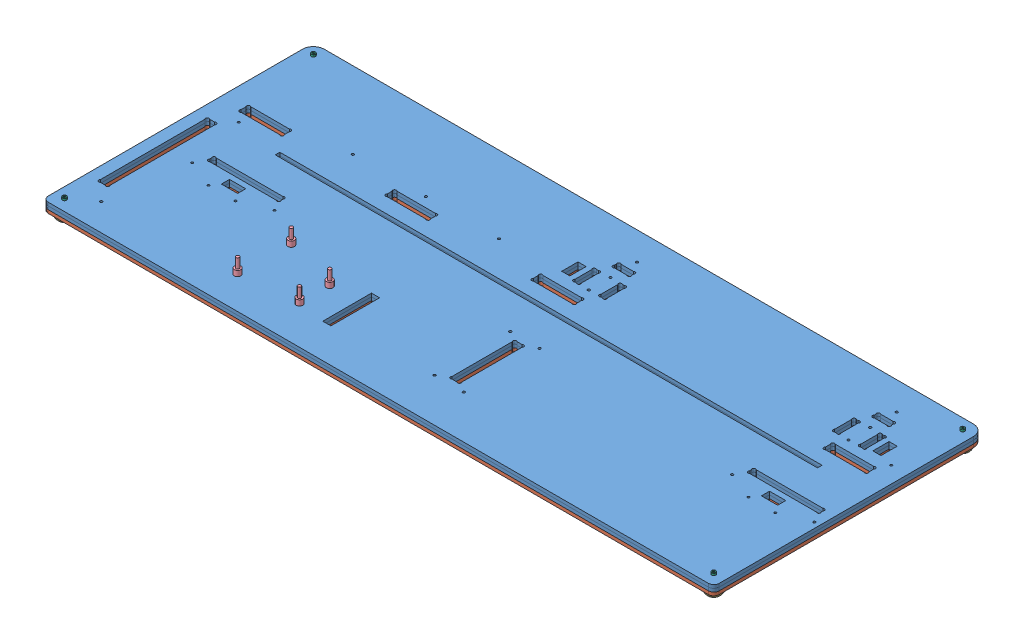
SolidWorks assembly socle-complet, configuration Défaut. Lengths in mm.
Overall size (621.62 30.74 251.62).
21 component instances, 6 part files, 49 mates.
Components (placement in the parent):
- socle-1-1: socle-1 [Défaut] at (-302.5453 40.1785 745) size (620 3 250)
- socle-1-2: socle-1 [Défaut] at (-302.5453 37.1785 745) size (620 3 250)
- socle-2-3: socle-2 [Défaut] at (-302.5453 34.1785 745) size (620 3 250)
- socle-patin-ecrou_m2-1: socle-patin-ecrou_m2 [Défaut] at (-292.5453 34.1785 735) x (0.367083 0 0.930188) z (-0.930188 0 0.367083) size (16 7.74 16)
- socle-patin-ecrou_m2-2: socle-patin-ecrou_m2 [Défaut] at (-292.5453 34.1785 505) x (-0.622025 0 0.782997) z (-0.782997 0 -0.622025) size (16 7.74 16)
- socle-patin-ecrou_m2-3: socle-patin-ecrou_m2 [Défaut] at (307.4547 34.1785 505) x (0.367083 0 0.930188) z (-0.930188 0 0.367083) size (16 7.74 16)
- socle-patin-ecrou_m2-4: socle-patin-ecrou_m2 [Défaut] at (307.4547 34.1785 735) x (0.367083 0 0.930188) z (-0.930188 0 0.367083) size (16 7.74 16)
- socle-carte_pied-1: socle-carte_pied [Défaut] at (-152.5453 38.1785 715) x (0 1 0) z (-0.920347 0 -0.391102) size (19 6 6)
- socle-carte_pied-2: socle-carte_pied [Défaut] at (-151.2753 38.1785 666.74) x (0 1 0) z (-0.842592 0 -0.538553) size (19 6 6)
- socle-carte_pied-3: socle-carte_pied [Défaut] at (-100.4753 38.1785 681.98) x (0 1 0) z (-0.819102 0 -0.573647) size (19 6 6)
- socle-carte_pied-4: socle-carte_pied [Défaut] at (-100.4753 38.1785 709.92) x (0 1 0) z (0.984574 0 0.174968) size (19 6 6)
- ecrou-h-1: ecrou-h [6007 HU M2] at (-292.5453 31.1785 735) size (4 1.6 4.62)
- vis-chc-1: vis-chc [Vis CHC M2x16] at (-292.5453 43.1785 735) x (0.999999 0 -0.001395) z (0.001395 0 0.999999) size (3.8 18 3.8)
- vis-chc-2: vis-chc [Vis CHC M2x16] at (307.4547 43.1785 735) x (0.999999 0 -0.001395) z (0.001395 0 0.999999) size (3.8 18 3.8)
- vis-chc-3: vis-chc [Vis CHC M2x16] at (-292.5453 43.1785 505) x (0.610012 0 -0.792392) z (0.792392 0 0.610012) size (3.8 18 3.8)
- vis-chc-4: vis-chc [Vis CHC M2x16] at (307.4547 43.1785 505) x (0.999999 0 -0.001395) z (0.001395 0 0.999999) size (3.8 18 3.8)
- ecrou-h-2: ecrou-h [6007 HU M2] at (307.4547 31.1785 735) size (4 1.6 4.62)
- ecrou-h-3: ecrou-h [6007 HU M2] at (307.4547 31.1785 505) size (4 1.6 4.62)
- ecrou-h-4: ecrou-h [6007 HU M2] at (-292.5453 31.1785 505) size (4 1.6 4.62)
- socle-patin-ecrou_m2-5: socle-patin-ecrou_m2 [Défaut] at (22.4547 34.1785 521) x (-0.256954 0 0.966424) z (-0.966424 0 -0.256954) size (16 7.74 16)
- socle-patin-ecrou_m2-6: socle-patin-ecrou_m2 [Défaut] at (19.4547 34.1785 705) x (0.367083 0 0.930188) z (-0.930188 0 0.367083) size (16 7.74 16)
Mates (geometry in assembly coordinates):
- Coïncidente1: coincident anti-aligned: plane of socle-1-1 through (-292.5453 40.1785 505) normal (0 -1 0); plane of socle-1-2 through (-292.5453 40.1785 505) normal (0 1 0)
- Coïncidente2: coincident aligned: plane of socle-1-1 through (-302.5453 43.1785 745) normal (0 0 1); plane of socle-1-2 through (-302.5453 40.1785 745) normal (0 0 1)
- Coïncidente3: coincident aligned: plane of socle-1-1 through (-302.5453 43.1785 505) normal (-1 0 0); plane of socle-1-2 through (-302.5453 40.1785 505) normal (-1 0 0)
- Coïncidente4: coincident anti-aligned: plane of socle-1-2 through (-292.5453 37.1785 505) normal (0 -1 0); plane of socle-3 through (-292.5453 37.1785 505) normal (0 1 0)
- Coïncidente5: coincident aligned: plane of socle-1-2 through (-302.5453 40.1785 745) normal (0 0 1); plane of socle-3 through (-302.5453 37.1785 745) normal (0 0 1)
- Coïncidente6: coincident aligned: plane of socle-1-2 through (-302.5453 40.1785 505) normal (-1 0 0); plane of socle-3 through (-302.5453 37.1785 505) normal (-1 0 0)
- Coaxiale1: concentric anti-aligned: cylinder of socle-3 through (-292.5453 37.1785 735) axis (0 -1 0) radius 1.1; cylinder of socle-patin-ecrou_m2-1 through (-292.5453 26.1785 735) axis (0 1 0) radius 1
- Coïncidente7: coincident anti-aligned: plane of socle-3 through (-292.5453 34.1785 505) normal (0 -1 0); plane of socle-patin-ecrou_m2-1 through (-295.482 34.1785 727.5585) normal (0 1 0)
- Coaxiale2: concentric anti-aligned: cylinder of socle-3 through (307.4547 37.1785 735) axis (0 -1 0) radius 1.1; cylinder of socle-patin-ecrou_m2-4 through (307.4547 26.1785 735) axis (0 1 0) radius 1
- Coaxiale3: concentric anti-aligned: cylinder of socle-3 through (307.4547 37.1785 505) axis (0 -1 0) radius 1.1; cylinder of socle-patin-ecrou_m2-3 through (307.4547 26.1785 505) axis (0 1 0) radius 1
- Coaxiale4: concentric anti-aligned: cylinder of socle-3 through (-292.5453 37.1785 505) axis (0 -1 0) radius 1.1; cylinder of socle-patin-ecrou_m2-2 through (-292.5453 26.1785 505) axis (0 1 0) radius 1
- Coïncidente8: coincident anti-aligned: plane of socle-3 through (-292.5453 34.1785 505) normal (0 -1 0); plane of socle-patin-ecrou_m2-2 through (-287.5691 34.1785 498.736) normal (0 1 0)
- Coïncidente9: coincident anti-aligned: plane of socle-3 through (-292.5453 34.1785 505) normal (0 -1 0); plane of socle-patin-ecrou_m2-3 through (304.518 34.1785 497.5585) normal (0 1 0)
- Coïncidente10: coincident anti-aligned: plane of socle-3 through (-292.5453 34.1785 505) normal (0 -1 0); plane of socle-patin-ecrou_m2-4 through (304.518 34.1785 727.5585) normal (0 1 0)
- Parallèle1: parallel anti-aligned: plane of socle-3 through (317.4547 37.1785 505) normal (1 0 0); plane of socle-patin-ecrou_m2-4 through (309.4725 26.2413 736.165) normal (-1 0 0)
- Parallèle2: parallel anti-aligned: plane of socle-3 through (317.4547 37.1785 505) normal (1 0 0); plane of socle-patin-ecrou_m2-3 through (309.4725 26.2413 506.165) normal (-1 0 0)
- Parallèle3: parallel anti-aligned: plane of socle-3 through (-302.5453 37.1785 505) normal (-1 0 0); plane of socle-patin-ecrou_m2-1 through (-294.5631 26.2413 733.835) normal (1 0 0)
- Parallèle4: parallel anti-aligned: plane of socle-3 through (-302.5453 37.1785 505) normal (-1 0 0); plane of socle-patin-ecrou_m2-2 through (-294.5631 26.2413 503.835) normal (1 0 0)
- Coaxiale5: concentric aligned: cylinder of socle-1-1 through (-152.5453 40.1785 715) axis (0 1 0) radius 1.59; cylinder of socle-carte_pied-1 through (-152.5453 57.1785 715) axis (0 1 0) radius 1.5
- Coaxiale6: concentric aligned: cylinder of socle-1-1 through (-100.4753 40.1785 709.92) axis (0 1 0) radius 1.59; cylinder of socle-carte_pied-4 through (-100.4753 57.1785 709.92) axis (0 1 0) radius 1.5
- Coaxiale7: concentric aligned: cylinder of socle-1-1 through (-100.4753 40.1785 681.98) axis (0 1 0) radius 1.59; cylinder of socle-carte_pied-3 through (-100.4753 57.1785 681.98) axis (0 1 0) radius 1.5
- Coaxiale8: concentric aligned: cylinder of socle-1-1 through (-151.2753 40.1785 666.74) axis (0 1 0) radius 1.59; cylinder of socle-carte_pied-2 through (-151.2753 57.1785 666.74) axis (0 1 0) radius 1.5
- Coïncidente11: coincident anti-aligned: plane of socle-1-1 through (-292.5453 43.1785 505) normal (0 1 0); plane of socle-carte_pied-1 through (-151.9586 43.1785 713.6195) normal (0 -1 0)
- Coïncidente12: coincident anti-aligned: plane of socle-1-1 through (-292.5453 43.1785 505) normal (0 1 0); plane of socle-carte_pied-2 through (-150.4675 43.1785 665.4761) normal (0 -1 0)
- Coïncidente13: coincident anti-aligned: plane of socle-1-1 through (-292.5453 43.1785 505) normal (0 1 0); plane of socle-carte_pied-3 through (-99.6148 43.1785 680.7513) normal (0 -1 0)
- Coïncidente14: coincident anti-aligned: plane of socle-1-1 through (-292.5453 43.1785 505) normal (0 1 0); plane of socle-carte_pied-4 through (-100.7378 43.1785 711.3969) normal (0 -1 0)
- Coaxiale9: concentric anti-aligned: cylinder of socle-1-1 through (-292.5453 43.1785 735) axis (0 -1 0) radius 1.1; cylinder of vis-chc-1 through (-292.5453 27.1785 735) axis (0 1 0) radius 1
- Coïncidente15: coincident anti-aligned: plane of socle-1-1 through (-292.5453 43.1785 505) normal (0 1 0); plane of vis-chc-1 through (-292.5453 43.1785 735) normal (0 -1 0)
- Coaxiale10: concentric aligned: cylinder of ecrou-h-1 through (-292.5453 29.5785 735) axis (0 1 0) radius 0.7835; cylinder of vis-chc-1 through (-292.5453 27.1785 735) axis (0 1 0) radius 1
- Parallèle5: parallel anti-aligned: plane of socle-patin-ecrou_m2-1 through (-292.5453 26.2413 732.67) normal (0.5 0 0.866025); plane of ecrou-h-1 through (-292.5453 29.5785 732.6906) normal (-0.5 0 -0.866025)
- Coïncidente18: coincident anti-aligned: plane of socle-patin-ecrou_m2-1 through (-292.5453 31.1785 735) normal (0 -1 0); plane of ecrou-h-1 through (-290.5453 31.1785 733.8453) normal (0 1 0)
- Coaxiale11: concentric anti-aligned: cylinder of socle-1-1 through (307.4547 43.1785 735) axis (0 -1 0) radius 1.1; cylinder of vis-chc-2 through (307.4547 27.1785 735) axis (0 1 0) radius 1
- Coïncidente19: coincident aligned: plane of socle-1-1 through (-292.5453 43.1785 505) normal (0 1 0); circle of vis-chc-2
- Coaxiale12: concentric anti-aligned: cylinder of socle-1-1 through (307.4547 43.1785 505) axis (0 -1 0) radius 1.1; cylinder of vis-chc-4 through (307.4547 27.1785 505) axis (0 1 0) radius 1
- Coïncidente20: coincident anti-aligned: plane of socle-1-1 through (-292.5453 43.1785 505) normal (0 1 0); plane of vis-chc-4 through (307.4547 43.1785 505) normal (0 -1 0)
- Coaxiale13: concentric anti-aligned: cylinder of socle-1-1 through (-292.5453 43.1785 505) axis (0 -1 0) radius 1.1; cylinder of vis-chc-3 through (-292.5453 27.1785 505) axis (0 1 0) radius 1
- Coïncidente21: coincident anti-aligned: plane of socle-1-1 through (-292.5453 43.1785 505) normal (0 1 0); plane of vis-chc-3 through (-292.5453 43.1785 505) normal (0 -1 0)
- Coïncidente22: coincident anti-aligned: plane of socle-patin-ecrou_m2-2 through (-292.5453 31.1785 505) normal (0 -1 0); plane of ecrou-h-4 through (-290.5453 31.1785 503.8453) normal (0 1 0)
- Parallèle10: parallel anti-aligned: plane of socle-patin-ecrou_m2-2 through (-294.5631 26.2413 506.165) normal (0.5 0 -0.866025); plane of ecrou-h-4 through (-294.5453 29.5785 506.1547) normal (-0.5 0 0.866025)
- Coaxiale20: concentric aligned: cylinder of vis-chc-3 through (-292.5453 27.1785 505) axis (0 1 0) radius 1; cylinder of ecrou-h-4 through (-292.5453 29.5785 505) axis (0 1 0) radius 0.7835
- Coïncidente28: coincident anti-aligned: plane of socle-patin-ecrou_m2-3 through (307.4547 31.1785 505) normal (0 -1 0); plane of ecrou-h-3 through (309.4547 31.1785 503.8453) normal (0 1 0)
- Parallèle11: parallel anti-aligned: plane of socle-patin-ecrou_m2-3 through (305.4369 26.2413 506.165) normal (0.5 0 -0.866025); plane of ecrou-h-3 through (305.4547 29.5785 506.1547) normal (-0.5 0 0.866025)
- Coaxiale21: concentric aligned: cylinder of vis-chc-4 through (307.4547 27.1785 505) axis (0 1 0) radius 1; cylinder of ecrou-h-3 through (307.4547 29.5785 505) axis (0 1 0) radius 0.7835
- Coïncidente30: coincident anti-aligned: plane of socle-patin-ecrou_m2-4 through (307.4547 31.1785 735) normal (0 -1 0); plane of ecrou-h-2 through (309.4547 31.1785 733.8453) normal (0 1 0)
- Parallèle13: parallel anti-aligned: plane of socle-patin-ecrou_m2-4 through (307.4547 26.2413 737.33) normal (-0.5 0 -0.866025); plane of ecrou-h-2 through (307.4547 29.5785 737.3094) normal (0.5 0 0.866025)
- Coaxiale23: concentric aligned: cylinder of vis-chc-2 through (307.4547 27.1785 735) axis (0 1 0) radius 1; cylinder of ecrou-h-2 through (307.4547 29.5785 735) axis (0 1 0) radius 0.7835
- Coaxiale24: concentric aligned: cylinder of socle-2-3 through (22.4547 34.1785 521) axis (0 1 0) radius 1.1; cylinder of socle-patin-ecrou_m2-5 through (22.4547 26.1785 521) axis (0 1 0) radius 1
- Coaxiale25: concentric aligned: cylinder of socle-2-3 through (19.4547 34.1785 705) axis (0 1 0) radius 1.1; cylinder of socle-patin-ecrou_m2-6 through (19.4547 26.1785 705) axis (0 1 0) radius 1
- Coïncidente31: coincident anti-aligned: plane of socle-2-3 through (-292.5453 34.1785 505) normal (0 -1 0); plane of socle-patin-ecrou_m2-5 through (24.5103 34.1785 513.2686) normal (0 1 0)
